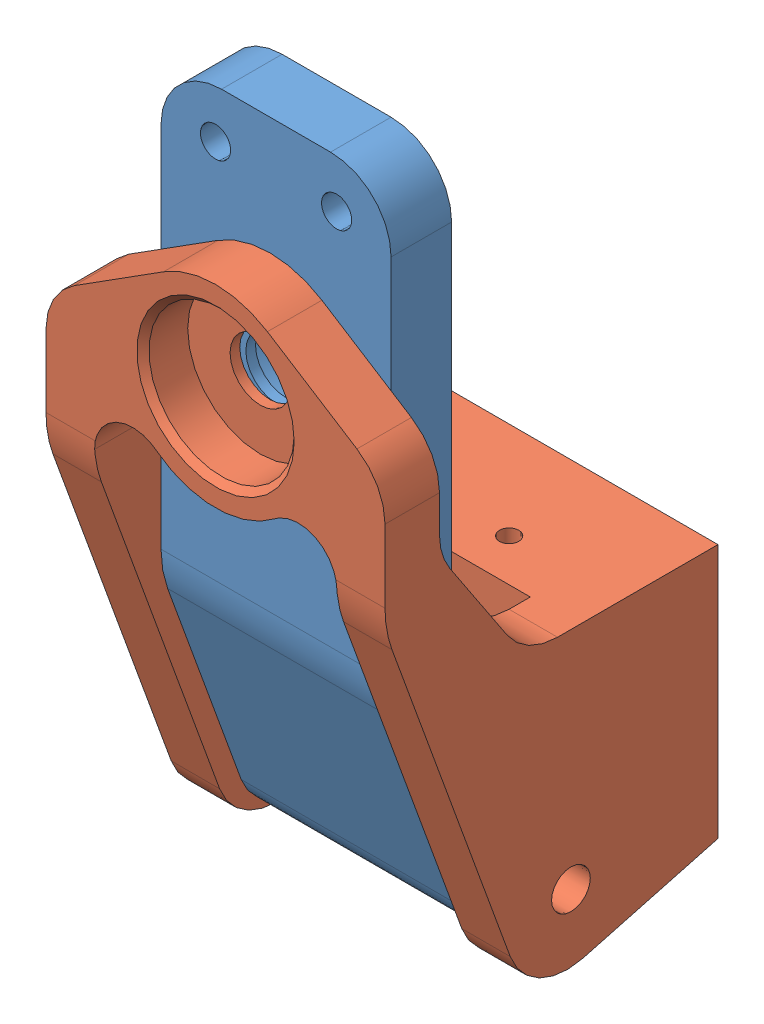
SolidWorks assembly shifterAssmebly, configuration Default. Lengths in mm.
Overall size (28 59.25 27.5).
2 component instances, 2 part files, 3 mates.
Components (placement in the parent):
- Step_MS01_-_Shifter_Lever-1: Step_MS01_-_Shifter_Lever [Default] at (88.8198 40.9162 49.2214) size (19 58.15 15.35)
- Step_MS01_-_Main_Body-1: Step_MS01_-_Main_Body [Default] at (88.3198 40.9162 49.2214) size (28 49.55 27.5)
Mates (geometry in assembly coordinates):
- Concentric1: concentric aligned: cylinder of Step_MS01_-_Shifter_Lever-1 through (98.3198 18.071 63.582) axis (-1 0 0) radius 2.75; cylinder of Step_MS01_-_Main_Body-1 through (102.3198 18.071 63.582) axis (-1 0 0) radius 1.6
- Coincident2: coincident anti-aligned: plane of Step_MS01_-_Shifter_Lever-1 through (98.3198 42.6477 66.7589) normal (1 0 0); plane of Step_MS01_-_Main_Body-1 through (98.3198 27.2573 68.6962) normal (-1 0 0)
- Coincident3: coincident anti-aligned: plane of Step_MS01_-_Shifter_Lever-1 through (98.3198 48.5228 74.4357) normal (0 0 1); plane of Step_MS01_-_Main_Body-1 through (88.3198 52.1445 74.4357) normal (0 0 -1)
